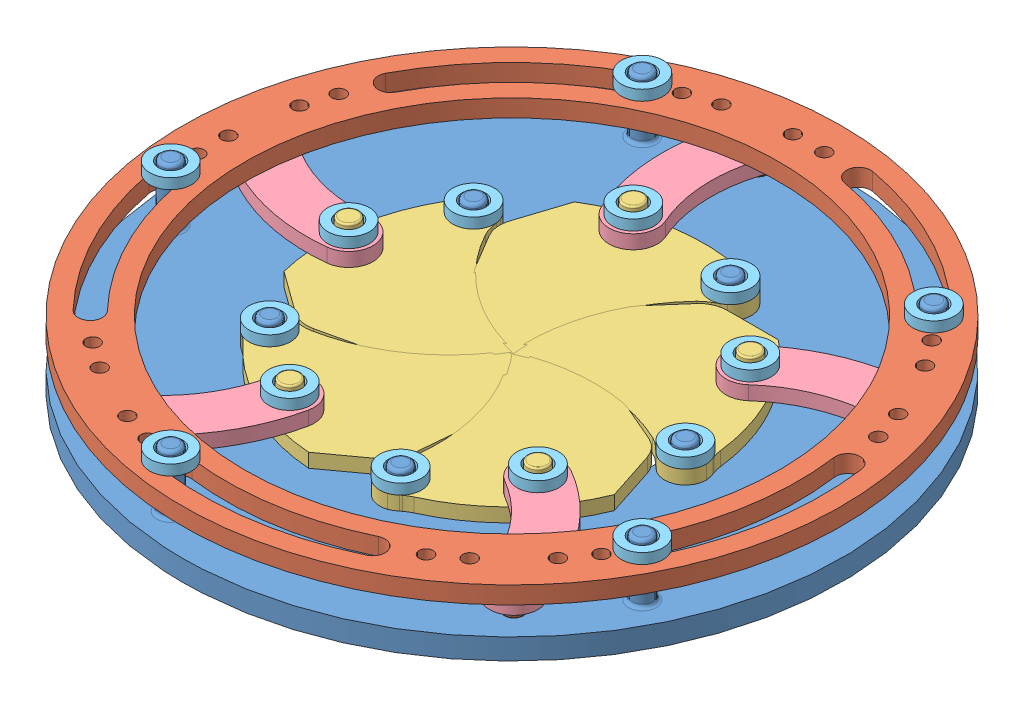
SolidWorks assembly Iris_Mech, configuration Default. Lengths in mm.
Overall size (128.98 11.5 128.98).
27 component instances, 5 part files, 13 mates.
Components (placement in the parent):
- 1_Base-2: 1_Base [Default] at origin size (95 11.5 95)
- 2_Ring-1: 2_Ring [Default] at (0 7 0) x (-0.48095 0 -0.876748) z (0.876748 0 -0.48095) size (95 6.5 95)
- 3_Slider-1: 3_Slider [Default] at (0.3112 3 0.0989) x (0.994496 0 -0.104778) z (0.104778 0 0.994496) size (28.27 6 27.5)
- 4_Link-2: 4_Link [Default] at (15.6134 3 -33.7281) x (-0.761854 0 -0.647749) z (0.647749 0 -0.761854) size (19.3 2 20.8)
- 3_Slider-12: 3_Slider [Default] at (0.1902 3 -0.2654) x (0.207666 0 -0.9782) z (0.9782 0 0.207666) size (28.27 6 27.5)
- 3_Slider-13: 3_Slider [Default] at (-0.1937 3 -0.2629) x (-0.866151 0 -0.499782) z (0.499782 0 -0.866151) size (28.27 6 27.5)
- 3_Slider-14: 3_Slider [Default] at (-0.3099 3 0.1029) x (-0.742977 0 0.669317) z (-0.669317 0 -0.742977) size (28.27 6 27.5)
- 3_Slider-15: 3_Slider [Default] at (0.0021 3 0.3266) x (0.406966 0 0.913443) z (-0.913443 0 0.406966) size (28.27 6 27.5)
- 4_Link-4: 4_Link [Default] at (-27.2525 3 -25.2718) x (-0.851472 0 0.524401) z (-0.524401 0 -0.851472) size (19.3 2 20.8)
- 4_Link-5: 4_Link [Default] at (-32.4564 3 18.1093) x (0.235616 0 0.971846) z (-0.971846 0 0.235616) size (19.3 2 20.8)
- 4_Link-6: 4_Link [Default] at (7.1934 3 36.4639) x (0.99709 0 0.076233) z (-0.076233 0 0.99709) size (19.3 2 20.8)
- 4_Link-7: 4_Link [Default] at (36.9021 3 4.4267) x (0.38062 0 -0.924732) z (0.924732 0 0.38062) size (19.3 2 20.8)
- 5_Holder-1: 5_Holder [Default] at (-6.4741 7 -23.9627) size (6 1.5 6)
- 5_Holder-2: 5_Holder [Default] at (7.7254 5 -23.7764) size (6 1.5 6)
- 5_Holder-3: 5_Holder [Default] at (-19.5216 9.5 -38.3133) x (0.97165 0 -0.236425) z (0.236425 0 0.97165) size (6 1.5 6)
- 5_Holder-11: 5_Holder [Default] at (-42.4706 9.5 6.7267) x (0.075403 0 -0.997153) z (0.997153 0 0.075403) size (6 1.5 6)
- 5_Holder-12: 5_Holder [Default] at (-6.7267 9.5 42.4706) x (-0.925048 0 -0.379849) z (0.379849 0 -0.925048) size (6 1.5 6)
- 5_Holder-13: 5_Holder [Default] at (38.3133 9.5 19.5216) x (-0.647114 0 0.762393) z (-0.762393 0 -0.647114) size (6 1.5 6)
- 5_Holder-14: 5_Holder [Default] at (30.4056 9.5 -30.4056) x (0.52511 0 0.851034) z (-0.851034 0 0.52511) size (6 1.5 6)
- 5_Holder-15: 5_Holder [Default] at (-20.2254 5 -14.6946) x (0.309017 0 -0.951057) z (0.951057 0 0.309017) size (6 1.5 6)
- 5_Holder-16: 5_Holder [Default] at (-20.2254 5 14.6946) x (-0.809017 0 -0.587785) z (0.587785 0 -0.809017) size (6 1.5 6)
- 5_Holder-17: 5_Holder [Default] at (7.7254 5 23.7764) x (-0.809017 0 0.587785) z (-0.587785 0 -0.809017) size (6 1.5 6)
- 5_Holder-18: 5_Holder [Default] at (25 5 0) x (0.309017 0 0.951057) z (-0.951057 0 0.309017) size (6 1.5 6)
- 5_Holder-19: 5_Holder [Default] at (-24.7905 7 -1.2476) x (0.309017 0 -0.951057) z (0.951057 0 0.309017) size (6 1.5 6)
- 5_Holder-20: 5_Holder [Default] at (-8.8472 7 23.1916) x (-0.809017 0 -0.587785) z (0.587785 0 -0.809017) size (6 1.5 6)
- 5_Holder-21: 5_Holder [Default] at (19.3226 7 15.5808) x (-0.809017 0 0.587785) z (-0.587785 0 -0.809017) size (6 1.5 6)
- 5_Holder-22: 5_Holder [Default] at (20.7893 7 -13.5621) x (0.309017 0 0.951057) z (-0.951057 0 0.309017) size (6 1.5 6)
Mates (geometry in assembly coordinates):
- Concentric1: concentric aligned: circle of 1_Base-2; circle of 2_Ring-1
- Coincident1: coincident anti-aligned: plane of 1_Base-2 through (0 3 0) normal (0 1 0); plane of 3_Slider-1 through (15.3382 3 -13.4383) normal (0 -1 0)
- Distance1: distance = 4 mm anti-aligned: plane of 2_Ring-1 through (0 7 0) normal (0 -1 0); plane of 1_Base-2 through (0 3 0) normal (0 1 0)
- Concentric6: concentric aligned: circle of 4_Link-2; circle of 2_Ring-1
- Coincident13: coincident anti-aligned: plane of 2_Ring-1 through (0 7 0) normal (0 -1 0); plane of 4_Link-2 through (4.3517 7 -38.0846) normal (0 1 0)
- Concentric11: concentric aligned: circle of 4_Link-2; circle of 3_Slider-1
- Concentric12: concentric anti-aligned: circle of 1_Base-2; circle of 3_Slider-1
- Concentric13: concentric aligned: circle of 3_Slider-1; circle of 5_Holder-1
- Coincident14: coincident anti-aligned: plane of 4_Link-2 through (4.3517 7 -38.0846) normal (0 1 0); plane of 5_Holder-1 through (-6.4741 7 -23.9627) normal (0 -1 0)
- Concentric14: concentric aligned: circle of 1_Base-2; circle of 5_Holder-2
- Coincident15: coincident anti-aligned: plane of 3_Slider-1 through (15.3382 5 -13.4383) normal (0 1 0); plane of 5_Holder-2 through (7.7254 5 -23.7764) normal (0 -1 0)
- Concentric15: concentric aligned: circle of 1_Base-2; circle of 5_Holder-3
- Coincident16: coincident anti-aligned: plane of 2_Ring-1 through (0 9.5 0) normal (0 1 0); plane of 5_Holder-3 through (-19.5216 9.5 -38.3133) normal (0 -1 0)
